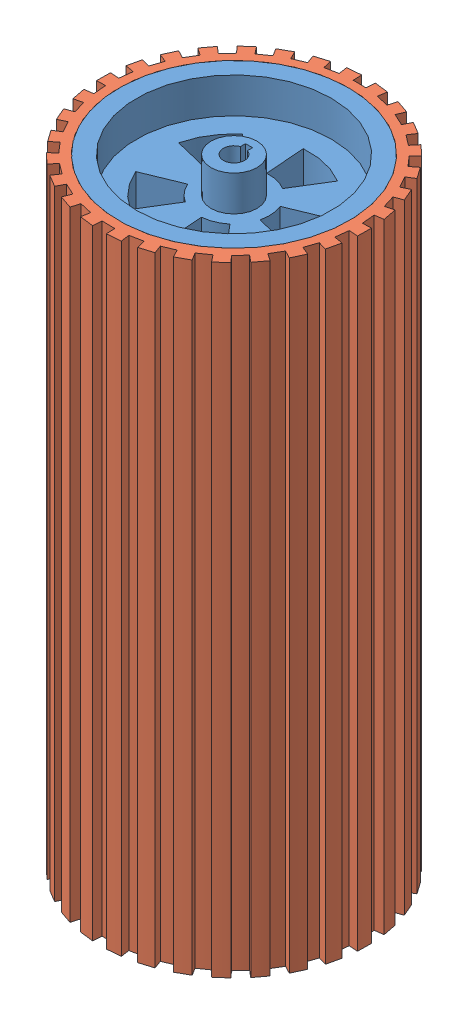
SolidWorks assembly wheel assembly, configuration Default. Lengths in mm.
Overall size (166.8 250 166.97).
2 component instances, 2 part files, 3 mates.
Components (placement in the parent):
- wheel rim-1: wheel rim [Default] at (102.1573 65.0647 363.573) size (130 250 130)
- wheel rubber-1: wheel rubber [Default] at (102.1573 65.0647 363.573) x (0.9927 0 0.120607) z (-0.120607 0 0.9927) size (149.8 250 150)
Mates (geometry in assembly coordinates):
- Concentric1: concentric aligned: circle of wheel rim-1; circle of wheel rubber-1
- Coincident1: coincident aligned: circle of wheel rim-1; circle of wheel rubber-1
- Lock1: lock: unknown of wheel rim-1; unknown of wheel rubber-1
